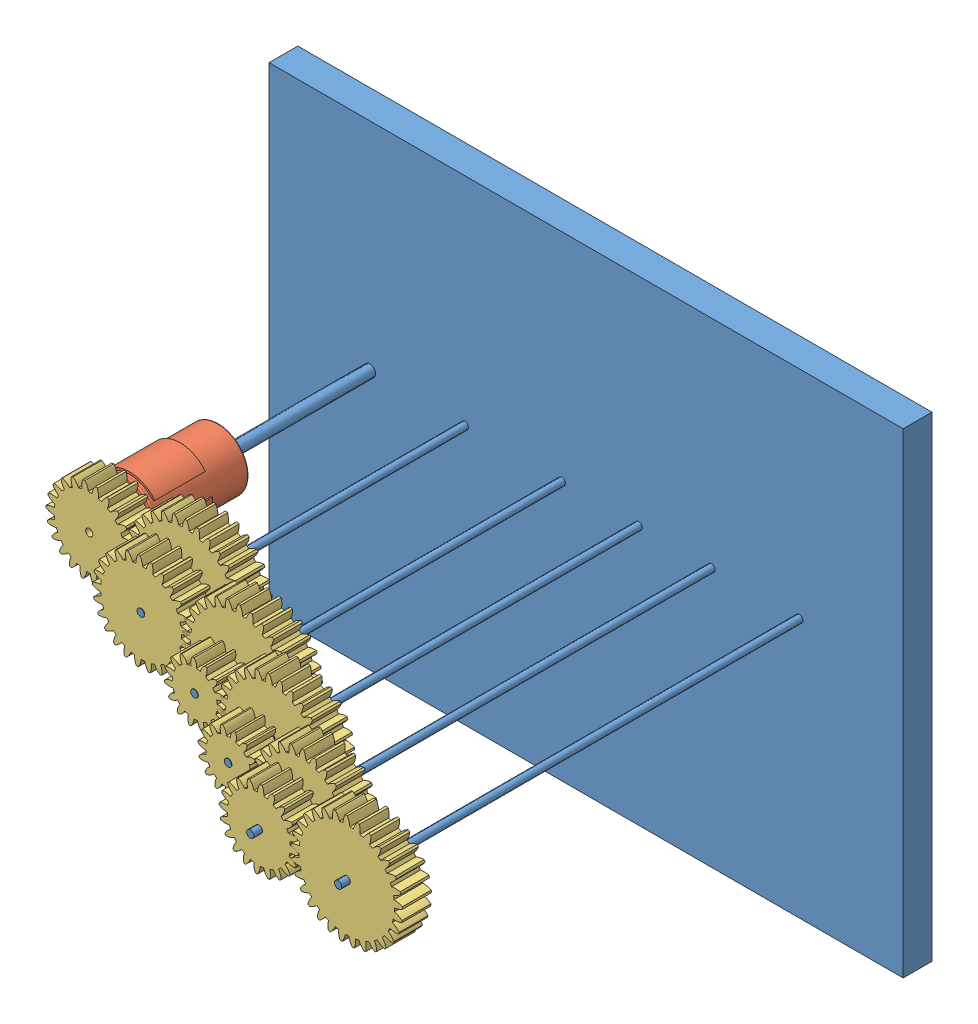
SolidWorks assembly Ensamblaje1, configuration Predeterminado. Lengths in mm.
Overall size (440 330 340).
12 component instances, 3 part files, 28 mates.
Components (placement in the parent):
- Base-2: Base [Predeterminado] at (-288.659 423.8281 342.8042) size (440 330 340)
- High Speed 775 Motor Low Noise DC 12V-24V Large Torque Motor Ball Bearing Tools-2: High Speed 775 Motor Low Noise DC 12V-24V Large Torque Motor Ball Bearing Tools [Default] at (-218.659 603.8281 467.8042) x (0 0 1) z (-0.350553 0.936543 0) size (96.7 43.88 45)
- spur gear_am-2: spur gear_am [Metric - Spur gear 2.5M 22T 20PA 20FW ---S22N75H50L5N] at (-218.659 603.8281 557.5042) x (0 0 -1) z (-0.9529 0.303284 0) size (20 59.57 60)
- spur gear_am-3: spur gear_am [Metric - Spur gear 2.5M 31T 20PA 20FW ---S31N75H50L5N] at (-152.659 603.8281 557.5042) x (0 0 -1) z (0.861426 -0.507883 0) size (20 82.36 82.46)
- spur gear_am-4: spur gear_am [Metric - Spur gear 2.5M 25T 20PA 20FW ---S25N75H50L5N] at (-152.659 603.8281 587.5042) x (0 0 -1) z (0.996713 -0.081015 0) size (20 67.32 67.44)
- spur gear_am-5: spur gear_am [Metric - Spur gear 2.5M 29T 20PA 20FW ---S29N75H50L5N] at (-85.459 603.8281 587.5042) x (0 0 -1) z (0.955202 0.295954 0) size (20 77.35 77.45)
- spur gear_am-6: spur gear_am [Metric - Spur gear 2.5M 15T 20PA 20FW ---S15N75H50L5N] at (-85.459 603.8281 617.5042) x (0 0 -1) z (-0.634454 -0.77296 0) size (20 42.15 42.37)
- spur gear_am-7: spur gear_am [Metric - Spur gear 2.5M 28T 20PA 20FW ---S28N75H50L5N] at (-32.159 603.8281 617.5042) x (0 0 -1) z (0.170602 -0.98534 0) size (20 74.68 74.68)
- spur gear_am-8: spur gear_am [Metric - Spur gear 2.5M 15T 20PA 20FW ---S15N75H50L5N] at (-32.159 603.8281 647.5042) x (0 0 -1) z (0.668598 0.743624 0) size (20 42.15 42.37)
- spur gear_am-9: spur gear_am [Metric - Spur gear 2.5M 25T 20PA 20FW ---S25N75H50L5N] at (18.341 603.8281 647.5042) x (0 0 -1) z (-0.892654 -0.450742 0) size (20 67.32 67.44)
- spur gear_am-10: spur gear_am [Metric - Spur gear 2.5M 20T 20PA 20FW ---S20N75H50L5N] at (18.341 603.8281 676.864) x (0 0 -1) z (-0.977134 0.212627 0) size (20 54.51 54.51)
- spur gear_am-11: spur gear_am [Metric - Spur gear 2.5M 29T 20PA 20FW ---S29N75H50L5N] at (79.341 603.8281 656.864) x (0 0 1) z (0.974939 0.222473 0) size (20 77.35 77.45)
Mates (geometry in assembly coordinates):
- Concéntrica4: concentric: cylinder of Base-2 through (-218.659 603.8281 362.8042) axis (0 0 1) radius 2.5; cylinder of High Speed 775 Motor Low Noise DC 12V-24V Large Torque Motor Ball Bearing Tools-2 through (-218.659 603.8281 457.8042) axis (0 0 1) radius 2.5
- Coincidente7: coincident: plane of Base-2 through (-288.659 423.8281 462.8042) normal (0 0 1); plane of High Speed 775 Motor Low Noise DC 12V-24V Large Torque Motor Ball Bearing Tools-2 through (-218.659 603.8281 462.8042) normal (0 0 -1)
- Concéntrica5: concentric: cylinder of High Speed 775 Motor Low Noise DC 12V-24V Large Torque Motor Ball Bearing Tools-2 through (-218.659 603.8281 554.5042) axis (0 0 -1) radius 2.5; cylinder of spur gear_am-2 through (-218.659 603.8281 507.5041) axis (0 0 1) radius 2.5
- Coincidente8: coincident: plane of High Speed 775 Motor Low Noise DC 12V-24V Large Torque Motor Ball Bearing Tools-2 through (-218.659 603.8281 537.5042) normal (0 0 1); plane of spur gear_am-2 through (-218.659 603.8281 537.5042) normal (0 0 -1)
- Coincidente15: coincident: plane of spur gear_am-2 through (-218.659 603.8281 557.5042) normal (0 0 1); plane of spur gear_am-3 through (-152.659 603.8281 557.5042) normal (0 0 1)
- Relación de posición de engranaje5: gear = 5 : 5 mm: cylinder of spur gear_am-3 through (-152.659 603.8281 507.5041) axis (0 0 1) radius 2.5; cylinder of spur gear_am-2 through (-218.659 603.8281 507.5041) axis (0 0 1) radius 2.5
- Concéntrica9: concentric: cylinder of spur gear_am-3 through (-152.659 603.8281 507.5041) axis (0 0 1) radius 2.5; cylinder of spur gear_am-4 through (-152.659 603.8281 537.5041) axis (0 0 1) radius 2.5
- Concéntrica10: concentric: cylinder of spur gear_am-5 through (-85.459 603.8281 537.5041) axis (0 0 1) radius 2.5; cylinder of spur gear_am-6 through (-85.459 603.8281 567.5041) axis (0 0 1) radius 2.5
- Relación de posición de engranaje6: gear = 5 : 5 mm: cylinder of spur gear_am-5 through (-85.459 603.8281 537.5041) axis (0 0 1) radius 2.5; cylinder of spur gear_am-4 through (-152.659 603.8281 537.5041) axis (0 0 1) radius 2.5
- Relación de posición de engranaje7: gear = 5 : 5 mm: cylinder of spur gear_am-6 through (-85.459 603.8281 567.5041) axis (0 0 1) radius 2.5; cylinder of spur gear_am-7 through (-32.159 603.8281 567.5041) axis (0 0 1) radius 2.5
- Concéntrica12: concentric: cylinder of spur gear_am-7 through (-32.159 603.8281 567.5041) axis (0 0 1) radius 2.5; cylinder of spur gear_am-8 through (-32.159 603.8281 597.5041) axis (0 0 1) radius 2.5
- Coincidente27: coincident: plane of spur gear_am-8 through (-32.159 603.8281 647.5042) normal (0 0 1); plane of spur gear_am-9 through (18.341 603.8281 647.5042) normal (0 0 1)
- Concéntrica13: concentric: cylinder of spur gear_am-9 through (18.341 603.8281 597.5041) axis (0 0 1) radius 2.5; cylinder of spur gear_am-10 through (18.341 603.8281 626.8639) axis (0 0 1) radius 2.5
- Coincidente31: coincident: plane of spur gear_am-10 through (18.341 603.8281 676.864) normal (0 0 1); plane of spur gear_am-11 through (79.341 603.8281 676.864) normal (0 0 1)
- Relación de posición de engranaje8: gear = 5 : 5 mm: cylinder of spur gear_am-10 through (18.341 603.8281 626.8639) axis (0 0 1) radius 2.5; cylinder of spur gear_am-11 through (79.341 603.8281 706.864) axis (0 0 -1) radius 2.5
- Concéntrica15: concentric: cylinder of Base-2 through (-152.659 603.8281 587.8042) axis (0 0 -1) radius 2.5; cylinder of spur gear_am-3 through (-152.659 603.8281 507.5041) axis (0 0 1) radius 2.5
- Relación de posición de engranaje9: gear = 5 : 5 mm: cylinder of spur gear_am-8 through (-32.159 603.8281 597.5041) axis (0 0 1) radius 2.5; cylinder of spur gear_am-9 through (18.341 603.8281 597.5041) axis (0 0 1) radius 2.5
- Bloquear3: lock: unknown of spur gear_am-3; unknown of spur gear_am-4
- Bloquear4: lock: unknown of spur gear_am-5; unknown of spur gear_am-6
- Coincidente39: coincident: plane of spur gear_am-6 through (-85.459 603.8281 617.5042) normal (0 0 1); plane of spur gear_am-7 through (-32.159 603.8281 617.5042) normal (0 0 1)
- Bloquear5: lock: unknown of spur gear_am-7; unknown of spur gear_am-8
- Coincidente41: coincident: plane of spur gear_am-4 through (-152.659 603.8281 587.5042) normal (0 0 1); plane of spur gear_am-5 through (-85.459 603.8281 587.5042) normal (0 0 1)
- Concéntrica30: concentric: cylinder of Base-2 through (-85.459 603.8281 617.8042) axis (0 0 -1) radius 2.5; cylinder of spur gear_am-5 through (-85.459 603.8281 537.5041) axis (0 0 1) radius 2.5
- Concéntrica31: concentric: cylinder of Base-2 through (-32.159 603.8281 647.8042) axis (0 0 -1) radius 2.5; cylinder of spur gear_am-7 through (-32.159 603.8281 567.5041) axis (0 0 1) radius 2.5
- Concéntrica32: concentric: cylinder of Base-2 through (18.341 603.8281 682.8042) axis (0 0 -1) radius 2.5; cylinder of spur gear_am-9 through (18.341 603.8281 597.5041) axis (0 0 1) radius 2.5
- Bloquear9: lock: unknown of spur gear_am-9; unknown of spur gear_am-10
- Coincidente47: coincident: plane of spur gear_am-10 through (18.341 603.8281 676.864) normal (0 0 1); plane of spur gear_am-11 through (79.341 603.8281 676.864) normal (0 0 1)
- Coincidente48: coincident: cylinder of Base-2 through (79.341 603.8281 682.8042) axis (0 0 -1) radius 2.5; circle of spur gear_am-11
